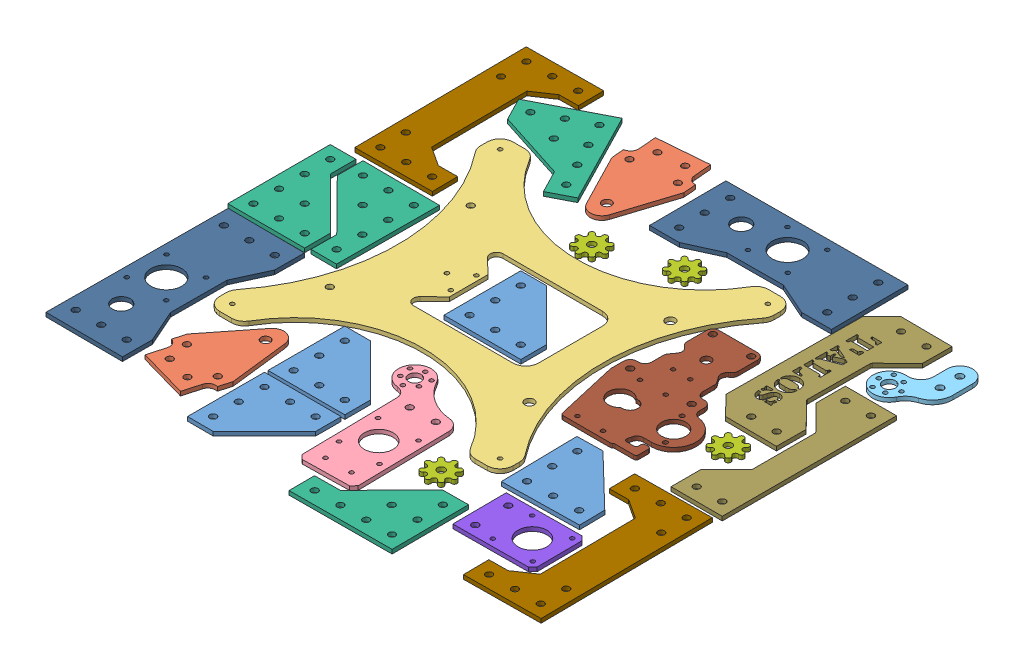
SolidWorks assembly Plate_Assembly, configuration Default. Lengths in mm.
Overall size (431.8 3.17 406.4).
25 component instances, 12 part files, 25 mates.
Components (placement in the parent):
- Corner Brackets 4mm-1: Corner Brackets 4mm [Default] at (162.0102 0 -179.9709) size (60 3.17 60)
- Corner Brackets 4mm-2: Corner Brackets 4mm [Default] at (130.7019 0 -73.9306) size (60 3.17 60)
- Corner Brackets 4mm-3: Corner Brackets 4mm [Default] at (130.5752 0 -71.3733) x (-0.002017 0 0.999998) z (-0.999998 0 -0.002017) size (60 3.17 60)
- Corner Brackets 4mm-4: Corner Brackets 4mm [Default] at (296.9234 0 -89.9031) x (0.999843 0 -0.017699) z (0.017699 0 0.999843) size (60 3.17 60)
- Gantry Plates-1: Gantry Plates [Default] at (144.4521 0 -384.135) x (-0.996586 0 0.082562) z (-0.082562 0 -0.996586) size (52 3.17 78.25)
- Gantry Plates-2: Gantry Plates [Default] at (91.4525 0 -31.099) x (0.962193 0 0.272367) z (-0.272367 0 0.962193) size (52 3.17 78.25)
- HB Mounting Plate-1: HB Mounting Plate [New] at (176.3094 0 -209.5093) size (229 3.17 229)
- Lead Screw Plate with Motor-1: Lead Screw Plate with Motor [Default] at (222.3707 0 -27.5048) x (0.999837 0 -0.018064) z (0.018064 0 0.999837) size (61.7 3.12 111.88)
- Lead Screw Plate-1: Lead Screw Plate [Default] at (382.5808 0 -306.9702) size (44.88 3.17 55.7)
- Lower Bracket-1: Lower Bracket [Default] at (2.3007 0 -170.9744) size (60 3.17 80)
- Lower Bracket-2: Lower Bracket [Default] at (86.0339 0 -252.4904) x (-0.999985 0 -0.005524) z (0.005524 0 -0.999985) size (60 3.17 80)
- Lower Bracket-3: Lower Bracket [Default] at (98.4953 0 -382.6297) x (-0.889294 0 0.457336) z (-0.457336 0 -0.889294) size (60 3.17 80)
- Lower Bracket-4: Lower Bracket [Default] at (300.1131 0 -1.4345) x (-0.005779 0 -0.999983) z (0.999983 0 -0.005779) size (60 3.17 80)
- M4 Nut Knob-1: M4 Nut Knob [M3 Version] at (265.5802 0 -74.2526) size (24.5 3.17 24.5)
- M4 Nut Knob-2: M4 Nut Knob [M3 Version] at (361.0349 0 -202.8836) size (24.5 3.17 24.5)
- M4 Nut Knob-3: M4 Nut Knob [M3 Version] at (171.9022 0 -285.5414) size (24.5 3.17 24.5)
- M4 Nut Knob-4: M4 Nut Knob [M3 Version] at (224.7034 0 -305.1026) size (24.5 3.17 24.5)
- New Y Motor Mount-1: New Y Motor Mount [Default] at (347.5208 0 -63.5499) x (-0.00741 0 -0.999973) z (0.999973 0 -0.00741) size (42 3.17 62)
- Side Panels-1: Side Panels [Default] at (13.2995 0 -325.9805) x (0.009 0 0.99996) z (-0.99996 0 0.009) size (135 3.17 60)
- Side Panels-2: Side Panels [Default] at (404.3377 0 -80.2949) x (-0.010154 0 -0.999948) z (0.999948 0 -0.010154) size (135 3.17 60)
- Top Motor Plates-1: Top Motor Plates [Default] at (251.9585 0 -381.1639) x (-0.999988 0 0.004867) z (-0.004867 0 -0.999988) size (141.35 3.17 60)
- Top Motor Plates-2: Top Motor Plates [Default] at (5.1389 0 -97.3022) x (-0.005619 0 0.999984) z (-0.999984 0 -0.005619) size (141.35 3.17 60)
- X Carriage Universal-1: X Carriage Universal [With Cable Chain Mount] at (294.7917 0 -252.0614) size (83.1 3.17 118.5)
- Y Plate Idler (20x20_on_top)-1: Y Plate Idler (20x20_on_top) [Front] at (341.022 0 -289.3758) x (-0.00807 0 0.999967) z (-0.999967 0 -0.00807) size (136 3.17 55)
- Y Plate Idler (20x20_on_top)-2: Y Plate Idler (20x20_on_top) [Back] at (406.6449 0 -220.6096) x (0.000393 0 -1) z (1 0 0.000393) size (136 3.17 40)
Mates (geometry in assembly coordinates):
- Coincident1: coincident anti-aligned: plane of assembly through (0 0 0) normal (0 1 0); plane of HB Mounting Plate-1 through (176.3094 0 -49.5093) normal (0 -1 0)
- Coincident2: coincident anti-aligned: plane of assembly through (0 0 0) normal (0 1 0); plane of X Carriage Universal-1 through (328.7917 0 -192.5614) normal (0 -1 0)
- Coincident3: coincident anti-aligned: plane of assembly through (0 0 0) normal (0 1 0); plane of Y Plate Idler (20x20_on_top)-2 through (406.6449 0 -220.6096) normal (0 -1 0)
- Coincident4: coincident anti-aligned: plane of assembly through (0 0 0) normal (0 1 0); plane of Y Plate Idler (20x20_on_top)-1 through (341.022 0 -289.3758) normal (0 -1 0)
- Coincident5: coincident anti-aligned: plane of assembly through (0 0 0) normal (0 1 0); plane of Top Motor Plates-2 through (5.1389 0 -97.3022) normal (0 -1 0)
- Coincident6: coincident anti-aligned: plane of assembly through (0 0 0) normal (0 1 0); plane of Top Motor Plates-1 through (251.9585 0 -381.1639) normal (0 -1 0)
- Coincident7: coincident anti-aligned: plane of assembly through (0 0 0) normal (0 1 0); plane of Corner Brackets 4mm-4 through (296.9234 0 -89.9031) normal (0 -1 0)
- Coincident8: coincident anti-aligned: plane of assembly through (0 0 0) normal (0 1 0); plane of Corner Brackets 4mm-3 through (130.5752 0 -71.3733) normal (0 -1 0)
- Coincident9: coincident anti-aligned: plane of assembly through (0 0 0) normal (0 1 0); plane of Corner Brackets 4mm-2 through (130.7019 0 -73.9306) normal (0 -1 0)
- Coincident11: coincident anti-aligned: plane of assembly through (0 0 0) normal (0 1 0); plane of Lower Bracket-2 through (86.0339 0 -252.4904) normal (0 -1 0)
- Coincident12: coincident anti-aligned: plane of assembly through (0 0 0) normal (0 1 0); plane of Lower Bracket-1 through (2.3007 0 -170.9744) normal (0 -1 0)
- Coincident13: coincident anti-aligned: plane of assembly through (0 0 0) normal (0 1 0); plane of Lead Screw Plate-1 through (404.7608 0 -339.9702) normal (0 -1 0)
- Coincident14: coincident anti-aligned: plane of assembly through (0 0 0) normal (0 1 0); plane of Lead Screw Plate with Motor-1 through (193.0836 0 -126.1718) normal (0 -1 0)
- Coincident15: coincident anti-aligned: plane of assembly through (0 0 0) normal (0 1 0); plane of Gantry Plates-2 through (120.2827 0 -37.4881) normal (0 -1 0)
- Coincident16: coincident anti-aligned: plane of assembly through (0 0 0) normal (0 1 0); plane of Gantry Plates-1 through (119.6967 0 -368.0362) normal (0 -1 0)
- Coincident17: coincident anti-aligned: plane of assembly through (0 0 0) normal (0 1 0); plane of Corner Brackets 4mm-1 through (162.0102 0 -179.9709) normal (0 -1 0)
- Coincident18: coincident anti-aligned: plane of assembly through (0 0 0) normal (0 1 0); plane of M4 Nut Knob-1 through (263.6187 0 -84.1141) normal (0 -1 0)
- Coincident19: coincident anti-aligned: plane of assembly through (0 0 0) normal (0 1 0); plane of M4 Nut Knob-2 through (359.0733 0 -212.7451) normal (0 -1 0)
- Coincident20: coincident anti-aligned: plane of assembly through (0 0 0) normal (0 1 0); plane of M4 Nut Knob-3 through (169.9406 0 -295.4029) normal (0 -1 0)
- Coincident21: coincident anti-aligned: plane of assembly through (0 0 0) normal (0 1 0); plane of M4 Nut Knob-4 through (222.7419 0 -314.9641) normal (0 -1 0)
- Coincident22: coincident anti-aligned: plane of assembly through (0 0 0) normal (0 1 0); plane of Lower Bracket-3 through (98.4953 0 -382.6297) normal (0 -1 0)
- Coincident23: coincident anti-aligned: plane of assembly through (0 0 0) normal (0 1 0); plane of Lower Bracket-4 through (300.1131 0 -1.4345) normal (0 -1 0)
- Coincident24: coincident anti-aligned: plane of assembly through (0 0 0) normal (0 1 0); plane of Side Panels-2 through (404.3377 0 -80.2949) normal (0 -1 0)
- Coincident25: coincident anti-aligned: plane of assembly through (0 0 0) normal (0 1 0); plane of Side Panels-1 through (13.2995 0 -325.9805) normal (0 -1 0)
- Coincident26: coincident anti-aligned: plane of assembly through (0 0 0) normal (0 1 0); plane of New Y Motor Mount-1 through (347.5208 0 -63.5499) normal (0 -1 0)
